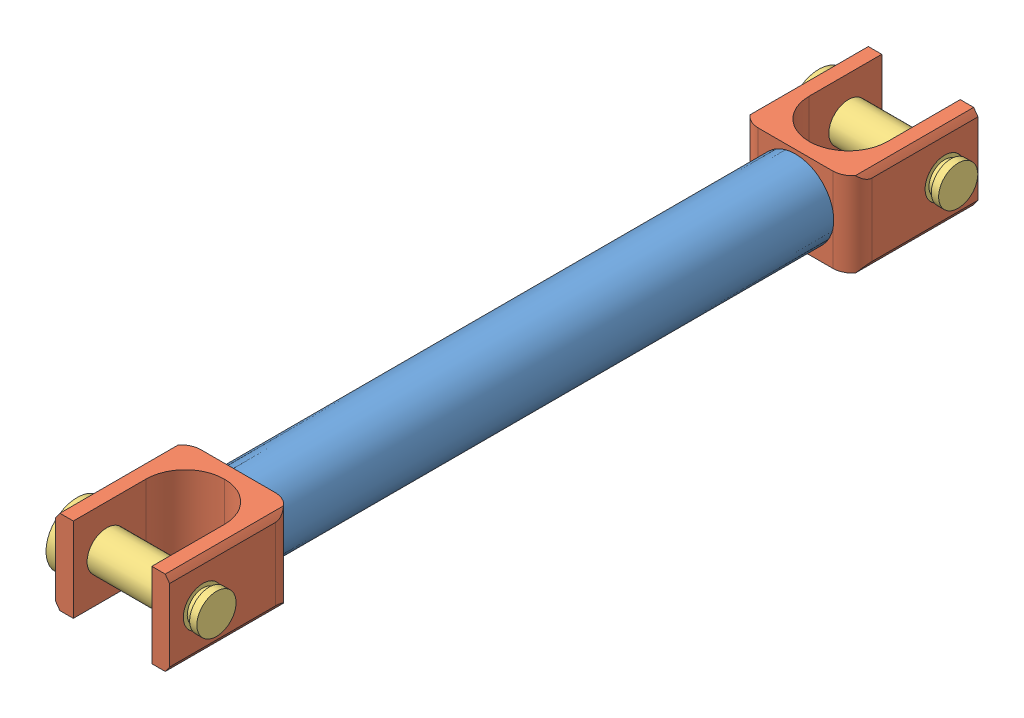
SolidWorks assembly motagem 2 flat, configuration Valor predeterminado. Lengths in mm.
Overall size (35.5 22.04 206).
5 component instances, 3 part files, 9 mates.
Components (placement in the parent):
- Peça2-1: Peça2 [Valor predeterminado] at (-1.1825 2.1764 72) size (19.5 19.5 144)
- pontas flat-1: pontas flat [Valor predeterminado] at (-1.1825 2.1764 215) size (29.05 22.04 32)
- pontas flat-2: pontas flat [Valor predeterminado] at (-1.1825 2.1764 73) x (-1 0 0) z (0 0 -1) size (29.05 22.04 32)
- pino shift-1: pino shift [Valor predeterminado] at (-18.7075 2.1764 238.5) x (0 0 -1) z (1 0 0) size (15.88 15.88 35.5)
- pino shift-2: pino shift [Valor predeterminado] at (-18.7075 2.1764 49.5) x (0 0 -1) z (1 0 0) size (15.88 15.88 35.5)
Mates (geometry in assembly coordinates):
- Coincidente1: coincident: plane of Peça2-1 through (-1.1825 2.1764 216) normal (0 0 1); plane of pontas flat-1 through (-1.1825 2.1764 216) normal (0 0 -1)
- Coincidente2: coincident: cylinder of Peça2-1 through (-1.1825 2.1764 216) axis (0 0 -1) radius 9.75; circle of pontas flat-1
- Coincidente3: coincident: plane of Peça2-1 through (-1.1825 2.1764 72) normal (0 0 -1); plane of pontas flat-2 through (-1.1825 2.1764 72) normal (0 0 1)
- Coincidente4: coincident: circle of Peça2-1; circle of pontas flat-2
- Paralelo1: parallel: plane of pontas flat-1 through (-15.7075 12.9264 215) normal (0 1 0); plane of pontas flat-2 through (13.3425 12.9264 73) normal (0 1 0)
- Concêntrico3: concentric: cylinder of pontas flat-1 through (-21.6575 2.1764 238.5) axis (1 0 0) radius 5; cylinder of pino shift-1 through (16.7925 2.1764 238.5) axis (-1 0 0) radius 5
- Coincidente14: coincident: plane of pontas flat-1 through (-15.7075 2.1764 212) normal (-1 0 0); plane of pino shift-1 through (-15.7075 2.1764 238.5) normal (1 0 0)
- Concêntrico4: concentric: cylinder of pontas flat-2 through (19.2925 2.1764 49.5) axis (-1 0 0) radius 5; cylinder of pino shift-2 through (16.7925 2.1764 49.5) axis (-1 0 0) radius 5
- Coincidente15: coincident: plane of pontas flat-2 through (-15.7075 2.1764 76) normal (-1 0 0); plane of pino shift-2 through (-15.7075 2.1764 49.5) normal (1 0 0)
